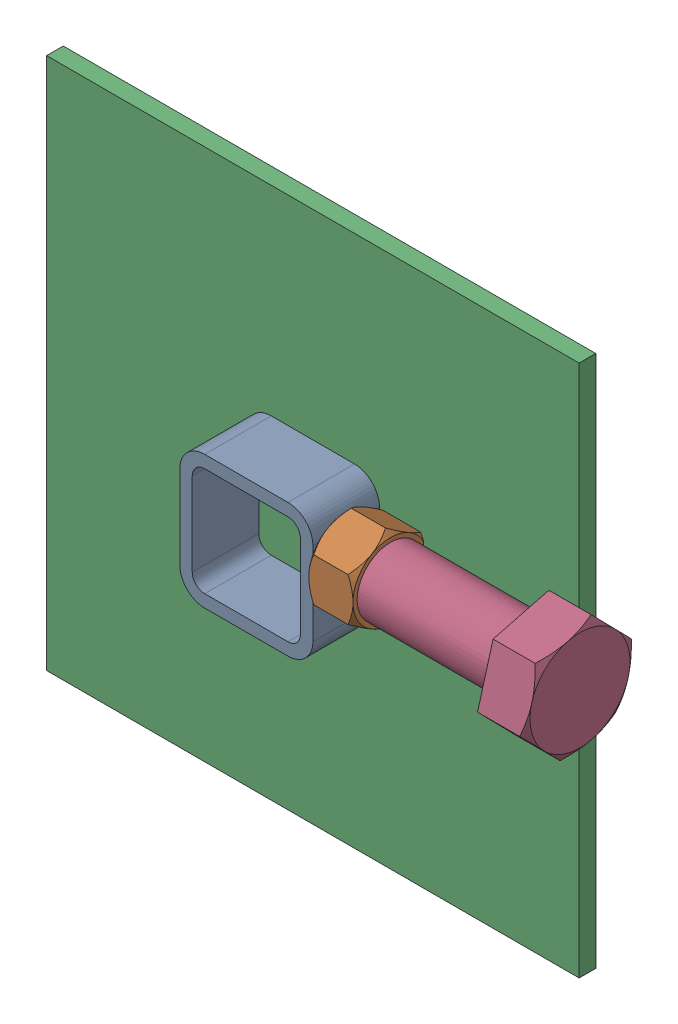
SolidWorks assembly 01-002-00-0(Default)-1, configuration Default. Lengths in mm.
Overall size (216.22 203.2 48.52).
5 component instances, 4 part files, 0 mates.
Components (placement in the parent):
- 01-005-00-0-5-1: 01-005-00-0-5 [Default] at origin size (67.69 50.8 28.57)
  - tube square_ai(PreviewCfg)-1: tube square_ai(PreviewCfg) [Default] at origin size (50.8 50.8 25.4)
  - hex nut_ai(HNUT 0.7500-10-D-C)-1: hex nut_ai(HNUT 0.7500-10-D-C) [Default] at (67.691 31.75 0) x (0 0 -1) z (1 0 0) size (28.57 33 16.89)
- 01-006-00-0-1: 01-006-00-0 [Default] at (-76.2 -76.2 -19.05) x (1 0 0) z (0 -1 0) size (203.2 6.35 203.2)
- hex bolt_ai(PreviewCfg)-1: hex bolt_ai(PreviewCfg) [Default] at (140.0175 31.75 0) x (-1 0 0) z (0 -0.268825 -0.963189) size (93.98 43.99 38.1)
